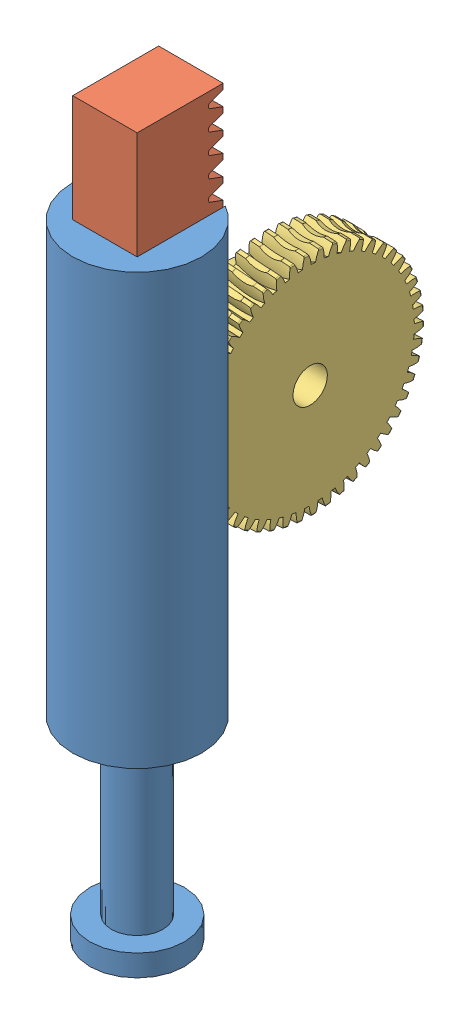
SolidWorks assembly Assem1, configuration Default. Lengths in mm.
Overall size (30 170 78.36).
3 component instances, 3 part files, 7 mates.
Components (placement in the parent):
- ur5link4-001-1: ur5link4-001 [Default] at origin size (30 145 30)
- 2485N243_METAL GEAR RACK - 20 DEGREE PRESSURE ANGLE-1: 2485N243_METAL GEAR RACK - 20 DEGREE PRESSURE ANGLE [2485N243] at (0 75 7.5) x (0 -1 0) z (1 0 0) size (100 20 15)
- 4037N133_PLASTIC WORM GEAR-1: 4037N133_PLASTIC WORM GEAR [4037N133] at (-5 51.5035 -35.2503) x (0 0.041876 0.999123) z (-1 0 0) size (54 53.96 20.06)
Mates (geometry in assembly coordinates):
- Coincident3: coincident anti-aligned: plane of ur5link4-001-1 through (0 25 7.5) normal (0 0 -1); plane of 2485N243_METAL GEAR RACK - 20 DEGREE PRESSURE ANGLE-1 through (7.5 25 7.5) normal (0 0 1)
- Coincident4: coincident anti-aligned: plane of ur5link4-001-1 through (7.5 25 0) normal (-1 0 0); plane of 2485N243_METAL GEAR RACK - 20 DEGREE PRESSURE ANGLE-1 through (7.5 25 -12.5) normal (1 0 0)
- Coincident5: coincident anti-aligned: plane of ur5link4-001-1 through (0 25 0) normal (0 1 0); plane of 2485N243_METAL GEAR RACK - 20 DEGREE PRESSURE ANGLE-1 through (0 25 7.5) normal (0 -1 0)
- Tangent4: tangent anti-aligned: plane of 2485N243_METAL GEAR RACK - 20 DEGREE PRESSURE ANGLE-1 through (-7.5 55.5336 -9.1492) normal (0 0.939693 -0.34202); face of 4037N133_PLASTIC WORM GEAR-1
- Parallel1: parallel aligned: plane of 2485N243_METAL GEAR RACK - 20 DEGREE PRESSURE ANGLE-1 through (-7.5 25 7.5) normal (-1 0 0); plane of 4037N133_PLASTIC WORM GEAR-1 through (-15 66.4903 -35.8785) normal (-1 0 0)
- Width1: width anti-aligned: plane of 4037N133_PLASTIC WORM GEAR-1 through (5 77.9802 -36.36) normal (1 0 0); plane of 2485N243_METAL GEAR RACK - 20 DEGREE PRESSURE ANGLE-1 through (-5 77.9802 -36.36) normal (-1 0 0); plane of 4037N133_PLASTIC WORM GEAR-1 through (-7.5 25 7.5) normal (-1 0 0); plane of 2485N243_METAL GEAR RACK - 20 DEGREE PRESSURE ANGLE-1 through (7.5 25 -12.5) normal (1 0 0)
- Tangent5: tangent anti-aligned: plane of 2485N243_METAL GEAR RACK - 20 DEGREE PRESSURE ANGLE-1 through (-7.5 25 -12.5) normal (0 0 -1); edge_curve of 4037N133_PLASTIC WORM GEAR-1
